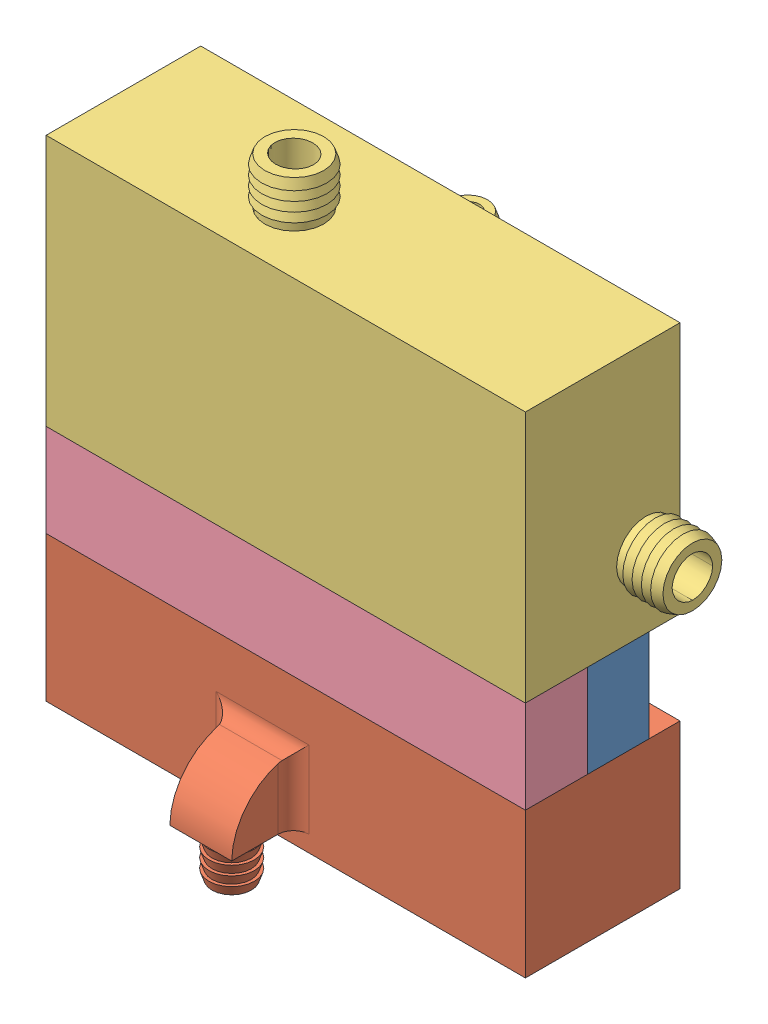
SolidWorks assembly Torus_7.5_50_Robust, configuration Default. Lengths in mm.
Overall size (185 183.28 95).
4 component instances, 4 part files, 11 mates.
Components (placement in the parent):
- 40_155_30_Bot_C-1: 40_155_30_Bot_C [Default] at (-7.3205 81.9517 184.5666) size (155 30 20)
- Elipse_Robust-1: Elipse_Robust [Default] at (-7.3205 154.9517 184.5666) size (155 56.74 70)
- Torus_Fen7.5_Robust-1: Torus_Fen7.5_Robust [Default] at (-7.3205 153.4853 184.5666) size (185 96.53 75)
- 40_155_30_Top-2: 40_155_30_Top [Default] at (-7.3205 81.9517 184.5666) size (155 30 20)
Mates (geometry in assembly coordinates):
- Coincident5: coincident anti-aligned: plane of 40_155_30_Top-1 through (-7.3205 81.9517 184.5666) normal (0 -1 0); plane of Elipse_Robust-1 through (-7.3205 81.9517 184.5666) normal (0 1 0)
- Coincident6: coincident aligned: plane of 40_155_30_Top-1 through (77.6795 111.9517 164.5666) normal (1 0 0); plane of Elipse_Robust-1 through (77.6795 194.9517 154.5666) normal (1 0 0)
- Coincident7: coincident anti-aligned: plane of 40_155_30_Top-1 through (-7.3205 111.9517 184.5666) normal (0 1 0); plane of Torus_Fen7.5_Robust-1 through (-7.3205 111.9517 184.5666) normal (0 -1 0)
- Concentric3: concentric anti-aligned: cylinder of 40_155_30_Top-1 through (-7.3205 111.9517 184.5666) axis (0 -1 0) radius 9; circle of Torus_Fen7.5_Robust-1
- Coincident9: coincident aligned: plane of 40_155_30_Top-1 through (77.6795 111.9517 164.5666) normal (1 0 0); plane of Torus_Fen7.5_Robust-1 through (77.6795 193.4853 154.5666) normal (1 0 0)
- Coincident11: coincident aligned: plane of 40_155_30_Bot_C-1 through (77.6795 111.9517 164.5666) normal (1 0 0); plane of Torus_Fen7.5_Robust-1 through (77.6795 193.4853 154.5666) normal (1 0 0)
- Coincident12: coincident aligned: plane of 40_155_30_Bot_C-1 through (77.6795 111.9517 164.5666) normal (1 0 0); plane of Elipse_Robust-1 through (77.6795 194.9517 154.5666) normal (1 0 0)
- Concentric4: concentric aligned: cylinder of 40_155_30_Bot_C-1 through (-7.3205 111.9517 184.5666) axis (0 -1 0) radius 9; cylinder of Elipse_Robust-1 through (-7.3205 123.9517 184.5666) axis (0 -1 0) radius 9
- Concentric5: concentric aligned: cylinder of 40_155_30_Bot_C-1 through (-7.3205 111.9517 184.5666) axis (0 -1 0) radius 9; cylinder of 40_155_30_Top-2 through (-7.3205 111.9517 184.5666) axis (0 -1 0) radius 9
- Coincident13: coincident anti-aligned: plane of Torus_Fen7.5_Robust-1 through (-7.3205 111.9517 184.5666) normal (0 -1 0); plane of 40_155_30_Top-2 through (-7.3205 111.9517 184.5666) normal (0 1 0)
- Coincident14: coincident aligned: plane of 40_155_30_Bot_C-1 through (77.6795 111.9517 164.5666) normal (1 0 0); plane of 40_155_30_Top-2 through (77.6795 111.9517 164.5666) normal (1 0 0)
